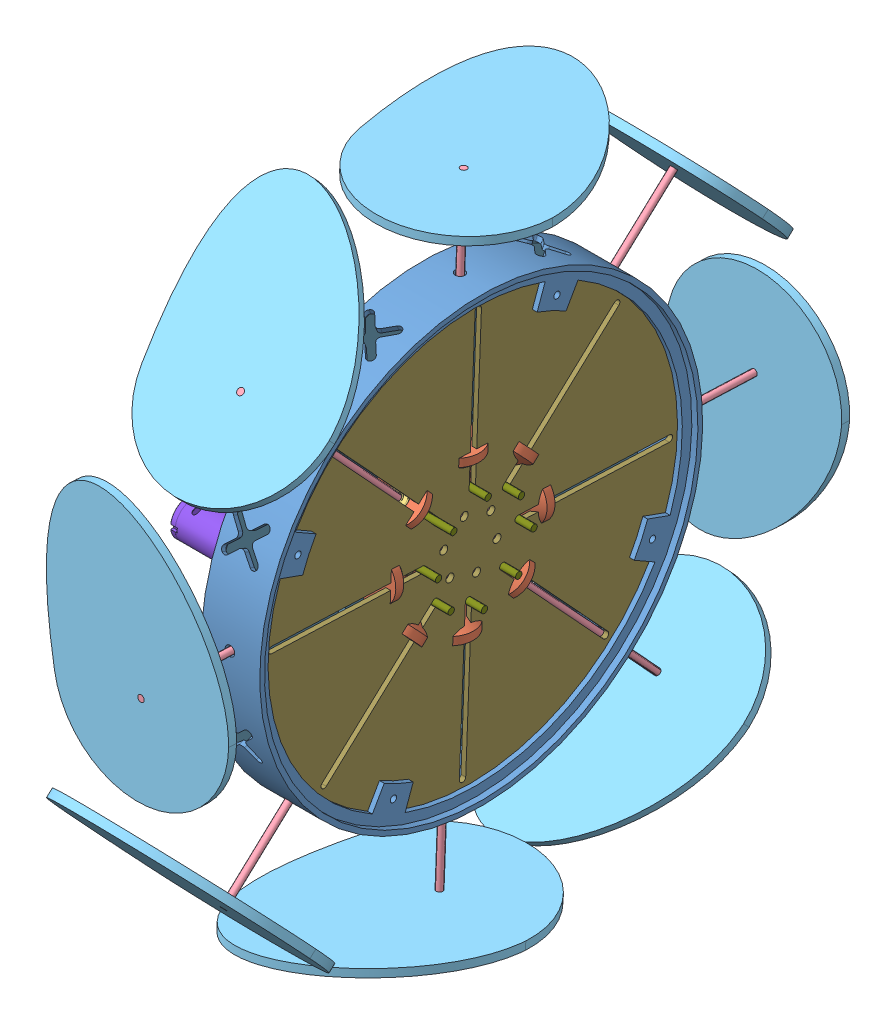
SolidWorks assembly armadillo-assembly, configuration Default. Lengths in mm.
Overall size (240.54 455.24 455.24).
84 component instances, 23 part files, 72 mates.
Components (placement in the parent):
- gear-plate-1: gear-plate [Default] at (127.9331 88.8526 55.989) size (3.8 120 80.27)
- 3mm-standoff-1: 3mm-standoff [Default] at (131.7331 77.626 -41.0696) size (22.7 6.93 6)
- 3mm-standoff-2: 3mm-standoff [Default] at (131.7331 15.626 23.2006) size (22.7 6.93 6)
- 3mm-standoff-3: 3mm-standoff [Default] at (131.7331 -26.374 -41.0696) size (22.7 6.93 6)
- gear-plate-2-1: gear-plate-2 [Default] at (154.4331 41.064 40.1689) size (3.8 120 80.27)
- 56-spur-2-1: 56-spur-2 [Default] at (146.1331 70.439 53.9289) x (-1 0 0) z (0 0.20976 -0.977753) size (21.9 85.49 85.49)
- 38-spur-2-2: 38-spur-2 [Default] at (146.0331 13.4884 13.6588) x (-1 0 0) z (0 -0.380955 0.924594) size (22.6 59.99 59.98)
- 25-tooth-spur-1: 25-tooth-spur [Default] at (134.0331 -9.561 53.9289) x (1 0 0) z (0 -0.929032 0.37) size (27.6 38.56 38.56)
- 30mm-3mm-standoff-1: 30mm-3mm-standoff [Default] at (97.9331 66.6963 -2.0848) size (30 6.93 6)
- 30mm-3mm-standoff-2: 30mm-3mm-standoff [Default] at (97.9331 66.6963 24.486) size (30 6.93 6)
- 30mm-3mm-standoff-3: 30mm-3mm-standoff [Default] at (97.9331 43.6853 11.2006) size (30 6.93 6)
- 30mm-3mm-standoff-4: 30mm-3mm-standoff [Default] at (97.9331 -15.4443 -2.0848) size (30 6.93 6)
- 30mm-3mm-standoff-5: 30mm-3mm-standoff [Default] at (127.9331 27.0214 87.9785) x (-1 0 0) z (0 -0.924225 -0.381849) size (30 6.93 6)
- 30mm-3mm-standoff-6: 30mm-3mm-standoff [Default] at (127.9331 50.0324 74.693) x (-1 0 0) z (0 -0.924225 -0.381849) size (30 6.93 6)
- motor-1: motor [Default] at (85.2831 63.839 53.9289) x (0 0 -1) z (0 -1 0) size (36.71 72.01 36.7)
- motor-2: motor [Default] at (85.2831 -2.961 53.9289) x (0 0 1) z (0 1 0) size (36.71 72.01 36.7)
- 6mm-coupler-1: 6mm-coupler [Default] at (92.9527 68.4137 78.816) x (0 -0.56228 -0.826947) z (1 0 0) size (15.04 15.04 20.11)
- gear-holder-1: gear-holder [Default] at (144.1331 70.439 53.9289) x (0 -0.977753 -0.20976) z (-1 0 0) size (75 75 12)
- shaft-1: shaft [Default] at (161.3831 70.439 53.9289) x (0 0.999313 0.03706) z (-1 0 0) size (6 6 100)
- facePlate-2.0-1: facePlate-2.0 [Default] at (211.3831 70.439 53.9289) x (0 0.678648 -0.734463) z (1 0 0) size (270 270 3)
- flange-coupling-1: flange-coupling [Default] at (207.3831 70.439 53.9289) x (0 0.678648 -0.734463) z (1 0 0) size (47 47 20)
- clutchPlate-2.0-1: clutchPlate-2.0 [Default] at (185.8831 70.439 53.9289) x (0 0.741879 0.670534) z (1 0 0) size (270 270 3.5)
- 40MM-3MM-STANDOFF-1: 40MM-3MM-STANDOFF [Default] at (144.1331 72.5384 32.6125) size (40 6.93 6)
- 40MM-3MM-STANDOFF-2: 40MM-3MM-STANDOFF [Default] at (144.1331 43.6265 6.481) size (40 6.93 6)
- 40MM-3MM-STANDOFF-3: 40MM-3MM-STANDOFF [Default] at (184.1331 123.1788 58.0008) x (-1 0 0) z (0 -0.924225 -0.381849) size (40 6.93 6)
- spoke-1: spoke [Default] at (199.3831 50.0786 75.9639) x (0 0.956269 0.292488) z (1 0 0) size (4 4 50)
- spoke-2: spoke [Default] at (199.3831 40.4609 55.113) x (0 -0.097119 0.995273) z (1 0 0) size (4 4 50)
- spoke-3: spoke [Default] at (199.3831 69.2549 23.9509) x (0 -0.097119 0.995273) z (1 0 0) size (4 4 50)
- spoke-4: spoke [Default] at (199.3831 48.404 33.5685) x (0 -0.097119 0.995273) z (1 0 0) size (4 4 50)
- spoke-5: spoke [Default] at (199.3831 90.7995 31.894) x (0 -0.097119 0.995273) z (1 0 0) size (4 4 50)
- spoke-6: spoke [Default] at (199.3831 92.474 74.2894) x (0 -0.097119 0.995273) z (1 0 0) size (4 4 50)
- spoke-7: spoke [Default] at (199.3831 100.4171 52.7449) x (0 -0.097119 0.995273) z (1 0 0) size (4 4 50)
- spoke-8: spoke [Default] at (199.3831 71.6231 83.907) x (0 -0.097119 0.995273) z (1 0 0) size (4 4 50)
- idler-gear-pin-1: idler-gear-pin [Default] at (143.9331 13.4884 13.6588) x (0 0 -1) z (1 0 0) size (6 6 40)
- actuation-shaft-2: actuation-shaft [Default] at (133.8831 -9.561 53.9289) x (0 0 -1) z (1 0 0) size (6 6 60)
- casing-1: casing [Default] at (217.3831 70.439 53.9289) x (-1 0 0) z (0 -0.418848 -0.908056) size (36.8 278 278)
- legs-1: legs [Default] at (175.4611 117.5432 79.7673) x (0 -0.678648 0.734463) z (1 0 0) size (189.45 175.5 148.14)
  - double-bearing-1: double-bearing [Default] at (12.9899 7.13 27.047) x (0 1 0) z (1 0 0) size (30.5 30.1 30.39)
  - 624RS-1: 624RS [Default] at (12.9899 22.13 26.047) size (13 13 5)
  - 624RS-2: 624RS [Default] at (12.9899 2.13 27.047) x (1 0 0) z (0 1 0) size (13 13 5)
  - shell-spoke-1: shell-spoke [Default] at (12.9899 -92.87 27.047) x (-0.999501 0 -0.031598) z (0 1 0) size (4 4 150)
  - shell-mockup-1: shell-mockup [Default] at (12.9899 -142.87 27.047) x (0.200645 0 -0.979664) z (0 1 0) size (116.49 169.53 5)
- legs-2: legs [Default] at (175.4611 122.0172 38.8917) x (0 0.039467 0.999221) z (1 0 0) size (189.45 175.5 148.14)
  - double-bearing-1: double-bearing [Default] at (12.9899 7.13 27.047) x (0 1 0) z (1 0 0) size (30.5 30.1 30.39)
  - 624RS-1: 624RS [Default] at (12.9899 22.13 26.047) size (13 13 5)
  - 624RS-2: 624RS [Default] at (12.9899 2.13 27.047) x (1 0 0) z (0 1 0) size (13 13 5)
  - shell-spoke-1: shell-spoke [Default] at (12.9899 -92.87 27.047) x (-0.999501 0 -0.031598) z (0 1 0) size (4 4 150)
  - shell-mockup-1: shell-mockup [Default] at (12.9899 -142.87 27.047) x (0.200645 0 -0.979664) z (0 1 0) size (116.49 169.53 5)
- legs-3: legs [Default] at (175.4611 96.2774 6.8247) x (0 0.734463 0.678648) z (1 0 0) size (189.45 175.5 148.14)
  - double-bearing-1: double-bearing [Default] at (12.9899 7.13 27.047) x (0 1 0) z (1 0 0) size (30.5 30.1 30.39)
  - 624RS-1: 624RS [Default] at (12.9899 22.13 26.047) size (13 13 5)
  - 624RS-2: 624RS [Default] at (12.9899 2.13 27.047) x (1 0 0) z (0 1 0) size (13 13 5)
  - shell-spoke-1: shell-spoke [Default] at (12.9899 -92.87 27.047) x (-0.999501 0 -0.031598) z (0 1 0) size (4 4 150)
  - shell-mockup-1: shell-mockup [Default] at (12.9899 -142.87 27.047) x (0.200645 0 -0.979664) z (0 1 0) size (116.49 169.53 5)
- legs-4: legs [Default] at (175.4611 55.4018 2.3508) x (0 0.999221 -0.039467) z (1 0 0) size (189.45 175.5 148.14)
  - double-bearing-1: double-bearing [Default] at (12.9899 7.13 27.047) x (0 1 0) z (1 0 0) size (30.5 30.1 30.39)
  - 624RS-1: 624RS [Default] at (12.9899 22.13 26.047) size (13 13 5)
  - 624RS-2: 624RS [Default] at (12.9899 2.13 27.047) x (1 0 0) z (0 1 0) size (13 13 5)
  - shell-spoke-1: shell-spoke [Default] at (12.9899 -92.87 27.047) x (-0.999501 0 -0.031598) z (0 1 0) size (4 4 150)
  - shell-mockup-1: shell-mockup [Default] at (12.9899 -142.87 27.047) x (0.200645 0 -0.979664) z (0 1 0) size (116.49 169.53 5)
- legs-5: legs [Default] at (175.4611 23.3348 28.0906) x (0 0.678648 -0.734463) z (1 0 0) size (189.45 175.5 148.14)
  - double-bearing-1: double-bearing [Default] at (12.9899 7.13 27.047) x (0 1 0) z (1 0 0) size (30.5 30.1 30.39)
  - 624RS-1: 624RS [Default] at (12.9899 22.13 26.047) size (13 13 5)
  - 624RS-2: 624RS [Default] at (12.9899 2.13 27.047) x (1 0 0) z (0 1 0) size (13 13 5)
  - shell-spoke-1: shell-spoke [Default] at (12.9899 -92.87 27.047) x (-0.999501 0 -0.031598) z (0 1 0) size (4 4 150)
  - shell-mockup-1: shell-mockup [Default] at (12.9899 -142.87 27.047) x (0.200645 0 -0.979664) z (0 1 0) size (116.49 169.53 5)
- legs-6: legs [Default] at (175.4611 18.8608 68.9662) x (0 -0.039467 -0.999221) z (1 0 0) size (189.45 175.5 148.14)
  - double-bearing-1: double-bearing [Default] at (12.9899 7.13 27.047) x (0 1 0) z (1 0 0) size (30.5 30.1 30.39)
  - 624RS-1: 624RS [Default] at (12.9899 22.13 26.047) size (13 13 5)
  - 624RS-2: 624RS [Default] at (12.9899 2.13 27.047) x (1 0 0) z (0 1 0) size (13 13 5)
  - shell-spoke-1: shell-spoke [Default] at (12.9899 -92.87 27.047) x (-0.999501 0 -0.031598) z (0 1 0) size (4 4 150)
  - shell-mockup-1: shell-mockup [Default] at (12.9899 -142.87 27.047) x (0.200645 0 -0.979664) z (0 1 0) size (116.49 169.53 5)
- legs-7: legs [Default] at (175.4611 44.6007 101.0332) x (0 -0.734463 -0.678648) z (1 0 0) size (189.45 175.5 148.14)
  - double-bearing-1: double-bearing [Default] at (12.9899 7.13 27.047) x (0 1 0) z (1 0 0) size (30.5 30.1 30.39)
  - 624RS-1: 624RS [Default] at (12.9899 22.13 26.047) size (13 13 5)
  - 624RS-2: 624RS [Default] at (12.9899 2.13 27.047) x (1 0 0) z (0 1 0) size (13 13 5)
  - shell-spoke-1: shell-spoke [Default] at (12.9899 -92.87 27.047) x (-0.999501 0 -0.031598) z (0 1 0) size (4 4 150)
  - shell-mockup-1: shell-mockup [Default] at (12.9899 -142.87 27.047) x (0.200645 0 -0.979664) z (0 1 0) size (116.49 169.53 5)
- legs-8: legs [Default] at (175.4611 85.4762 105.5071) x (0 -0.999221 0.039467) z (1 0 0) size (189.45 175.5 148.14)
  - double-bearing-1: double-bearing [Default] at (12.9899 7.13 27.047) x (0 1 0) z (1 0 0) size (30.5 30.1 30.39)
  - 624RS-1: 624RS [Default] at (12.9899 22.13 26.047) size (13 13 5)
  - 624RS-2: 624RS [Default] at (12.9899 2.13 27.047) x (1 0 0) z (0 1 0) size (13 13 5)
  - shell-spoke-1: shell-spoke [Default] at (12.9899 -92.87 27.047) x (-0.999501 0 -0.031598) z (0 1 0) size (4 4 150)
  - shell-mockup-1: shell-mockup [Default] at (12.9899 -142.87 27.047) x (0.200645 0 -0.979664) z (0 1 0) size (116.49 169.53 5)
Mates (geometry in assembly coordinates):
- Coincident1: coincident aligned: circle of gear-plate-1; circle of 3mm-standoff-1
- Coincident2: coincident aligned: circle of gear-plate-1; circle of 3mm-standoff-2
- Coincident3: coincident aligned: circle of gear-plate-1; circle of 3mm-standoff-3
- Concentric1: concentric aligned: circle of 3mm-standoff-1; circle of gear-plate-2-1
- Concentric2: concentric aligned: circle of 3mm-standoff-2; circle of gear-plate-2-1
- Coincident10: coincident anti-aligned: plane of 3mm-standoff-3 through (154.4331 -26.374 -41.0696) normal (1 0 0); plane of gear-plate-2-1 through (154.4331 70.439 53.9289) normal (-1 0 0)
- Coincident11: coincident anti-aligned: circle of gear-plate-1; circle of 56-spur-2-1
- Coincident12: coincident anti-aligned: circle of gear-plate-1; circle of 38-spur-2-2
- Concentric4: concentric aligned: circle of gear-plate-1; circle of 25-tooth-spur-1
- Coincident14: coincident aligned: plane of 38-spur-2-2 through (146.0331 13.4884 13.6588) normal (1 0 0); plane of 25-tooth-spur-1 through (146.0331 -9.561 53.9289) normal (1 0 0)
- GearMate1: gear = 38 : 56 mm: circle of 56-spur-2-1; circle of 38-spur-2-2
- GearMate2: gear = 38 : 25 mm: cylinder of 25-tooth-spur-1 through (146.0331 -9.561 53.9289) axis (-1 0 0) radius 3; cylinder of 38-spur-2-2 through (134.0331 13.4884 13.6588) axis (1 0 0) radius 3
- Coincident15: coincident aligned: circle of gear-plate-1; circle of 30mm-3mm-standoff-2
- Coincident16: coincident aligned: circle of gear-plate-1; circle of 30mm-3mm-standoff-3
- Coincident17: coincident aligned: circle of gear-plate-1; circle of 30mm-3mm-standoff-1
- Coincident18: coincident aligned: circle of gear-plate-1; circle of 30mm-3mm-standoff-4
- Coincident19: coincident anti-aligned: circle of gear-plate-1; circle of 30mm-3mm-standoff-6
- Coincident20: coincident anti-aligned: circle of gear-plate-1; circle of 30mm-3mm-standoff-5
- Concentric7: concentric aligned: circle of gear-plate-1; circle of motor-1
- Coincident22: coincident aligned: circle of 30mm-3mm-standoff-3; circle of motor-1
- Concentric8: concentric aligned: circle of 25-tooth-spur-1; circle of motor-2
- Coincident23: coincident anti-aligned: circle of 30mm-3mm-standoff-6; circle of motor-2
- Concentric9: concentric aligned: circle of motor-1; circle of 6mm-coupler-1
- Coincident24: coincident aligned: plane of motor-1 through (103.8831 63.839 53.9289) normal (-1 0 0); plane of 6mm-coupler-1 through (103.8831 70.439 53.9289) normal (-1 0 0)
- Concentric11: concentric anti-aligned: cylinder of 56-spur-2-1 through (153.6331 70.439 53.9289) axis (-1 0 0) radius 7.2; cylinder of gear-holder-1 through (140.1331 70.439 53.9289) axis (1 0 0) radius 7.2
- Coincident26: coincident anti-aligned: circle of 56-spur-2-1; circle of gear-holder-1
- Concentric12: concentric anti-aligned: cylinder of shaft-1 through (211.3831 70.439 53.9289) axis (-1 0 0) radius 3; circle of 6mm-coupler-1
- Coincident27: coincident aligned: plane of 6mm-coupler-1 through (111.3831 70.439 53.9289) normal (-1 0 0); plane of shaft-1 through (111.3831 70.439 53.9289) normal (-1 0 0)
- Concentric13: concentric aligned: cylinder of shaft-1 through (211.3831 70.439 53.9289) axis (-1 0 0) radius 3; circle of flange-coupling-1
- Coincident28: coincident aligned: plane of shaft-1 through (211.3831 70.439 53.9289) normal (1 0 0); plane of flange-coupling-1 through (211.3831 70.439 53.9289) normal (1 0 0)
- Coincident29: coincident aligned: circle of facePlate-2.0-1; circle of flange-coupling-1
- Coincident30: coincident aligned: circle of facePlate-2.0-1; circle of flange-coupling-1
- Concentric14: concentric anti-aligned: cylinder of shaft-1 through (211.3831 70.439 53.9289) axis (-1 0 0) radius 3; cylinder of clutchPlate-2.0-1 through (184.1331 70.439 53.9289) axis (1 0 0) radius 5
- Coincident31: coincident anti-aligned: circle of gear-holder-1; circle of 40MM-3MM-STANDOFF-1
- Coincident32: coincident anti-aligned: circle of gear-holder-1; circle of 40MM-3MM-STANDOFF-2
- Coincident33: coincident aligned: circle of gear-holder-1; circle of 40MM-3MM-STANDOFF-3
- Coincident34: coincident aligned: circle of clutchPlate-2.0-1; circle of 40MM-3MM-STANDOFF-1
- Slot1: slot anti-aligned: cylinder of spoke-1 through (174.3831 50.0786 75.9639) axis (1 0 0) radius 2; plane of facePlate-2.0-1 through (214.3831 51.5485 77.3201) normal (0 -0.734463 -0.678648); cylinder of facePlate-2.0-1 through (214.3831 50.0796 75.9628) axis (-1 0 0) radius 2
- Distance1: distance = 10 mm aligned: plane of facePlate-2.0-1 through (214.3831 70.439 53.9289) normal (1 0 0); plane of spoke-1 through (224.3831 50.0786 75.9639) normal (1 0 0)
- Slot2: slot aligned: cylinder of spoke-1 through (174.3831 50.0786 75.9639) axis (1 0 0) radius 2; cylinder of clutchPlate-2.0-1 through (184.1331 154.2557 -38.8059) axis (1 0 0) radius 153; cylinder of clutchPlate-2.0-1 through (184.1331 -0.4049 -49.0572) axis (1 0 0) radius 2
- Slot3: slot anti-aligned: cylinder of spoke-2 through (174.3831 40.4609 55.113) axis (1 0 0) radius 2; plane of facePlate-2.0-1 through (214.3831 40.5413 57.1114) normal (0 -0.039467 -0.999221); cylinder of facePlate-2.0-1 through (214.3831 40.4624 55.113) axis (-1 0 0) radius 2
- Distance2: distance = 10 mm aligned: plane of facePlate-2.0-1 through (214.3831 70.439 53.9289) normal (1 0 0); plane of spoke-2 through (224.3831 40.4609 55.113) normal (1 0 0)
- Slot4: slot aligned: cylinder of spoke-2 through (174.3831 40.4609 55.113) axis (1 0 0) radius 2; cylinder of clutchPlate-2.0-1 through (184.1331 195.2798 47.6228) axis (1 0 0) radius 157; cylinder of clutchPlate-2.0-1 through (184.1331 93.167 -68.9875) axis (1 0 0) radius 2
- Slot5: slot anti-aligned: cylinder of spoke-4 through (174.3831 48.404 33.5685) axis (1 0 0) radius 2; plane of facePlate-2.0-1 through (214.3831 47.0478 35.0384) normal (0 0.678648 -0.734463); cylinder of facePlate-2.0-1 through (214.3831 48.4051 33.5695) axis (-1 0 0) radius 2
- Slot6: slot aligned: cylinder of spoke-4 through (174.3831 48.404 33.5685) axis (1 0 0) radius 2; cylinder of clutchPlate-2.0-1 through (184.1331 163.1739 137.7456) axis (1 0 0) radius 157; cylinder of clutchPlate-2.0-1 through (184.1331 173.4251 -16.915) axis (1 0 0) radius 2
- Slot7: slot anti-aligned: cylinder of spoke-3 through (174.3831 69.2549 23.9509) axis (1 0 0) radius 2; plane of facePlate-2.0-1 through (214.3831 67.2566 24.0313) normal (0 0.999221 -0.039467); cylinder of facePlate-2.0-1 through (214.3831 69.255 23.9523) axis (-1 0 0) radius 2
- Slot8: slot aligned: cylinder of clutchPlate-2.0-1 through (184.1331 76.7451 178.7698) axis (1 0 0) radius 157; cylinder of spoke-3 through (174.3831 69.2549 23.9509) axis (1 0 0) radius 2; cylinder of clutchPlate-2.0-1 through (184.1331 193.3554 76.6569) axis (1 0 0) radius 2
- Distance3: distance = 10 mm aligned: plane of spoke-4 through (224.3831 48.404 33.5685) normal (1 0 0); plane of facePlate-2.0-1 through (214.3831 70.439 53.9289) normal (1 0 0)
- Distance4: distance = 10 mm aligned: plane of spoke-3 through (224.3831 69.2549 23.9509) normal (1 0 0); plane of facePlate-2.0-1 through (214.3831 70.439 53.9289) normal (1 0 0)
- Slot9: slot anti-aligned: cylinder of spoke-5 through (174.3831 90.7995 31.894) axis (1 0 0) radius 2; plane of facePlate-2.0-1 through (214.3831 92.2674 33.2523) normal (0 -0.734463 -0.678648); cylinder of facePlate-2.0-1 through (214.3831 155.2701 -37.879) axis (-1 0 0) radius 2
- Slot10: slot aligned: cylinder of spoke-5 through (174.3831 90.7995 31.894) axis (1 0 0) radius 2; cylinder of clutchPlate-2.0-1 through (184.1331 -13.3777 146.6638) axis (1 0 0) radius 153; cylinder of clutchPlate-2.0-1 through (184.1331 141.2829 156.915) axis (1 0 0) radius 2
- Slot11: slot anti-aligned: plane of facePlate-2.0-1 through (214.3831 100.4946 54.7434) normal (0 -0.039467 -0.999221); cylinder of spoke-7 through (174.3831 100.4171 52.7449) axis (1 0 0) radius 2; cylinder of facePlate-2.0-1 through (214.3831 195.3416 48.9956) axis (-1 0 0) radius 2
- Slot12: slot aligned: cylinder of spoke-7 through (174.3831 100.4171 52.7449) axis (1 0 0) radius 2; cylinder of clutchPlate-2.0-1 through (184.1331 -54.4018 60.2351) axis (1 0 0) radius 153; cylinder of clutchPlate-2.0-1 through (184.1331 47.7111 176.8453) axis (1 0 0) radius 2
- Slot13: slot anti-aligned: cylinder of spoke-6 through (174.3831 92.474 74.2894) axis (1 0 0) radius 2; plane of facePlate-2.0-1 through (214.3831 91.1156 75.7573) normal (0 0.678648 -0.734463); cylinder of facePlate-2.0-1 through (214.3831 162.2469 138.76) axis (-1 0 0) radius 2
- Slot14: slot aligned: cylinder of spoke-6 through (174.3831 92.474 74.2894) axis (1 0 0) radius 2; cylinder of clutchPlate-2.0-1 through (184.1331 -22.2959 -29.8878) axis (1 0 0) radius 153; cylinder of clutchPlate-2.0-1 through (184.1331 -32.5471 124.7729) axis (1 0 0) radius 2
- Slot15: slot anti-aligned: cylinder of spoke-8 through (174.3831 71.6231 83.907) axis (1 0 0) radius 2; plane of facePlate-2.0-1 through (214.3831 69.6246 83.9845) normal (0 0.999221 -0.039467); cylinder of facePlate-2.0-1 through (214.3831 75.3724 178.8316) axis (-1 0 0) radius 2
- Slot16: slot aligned: cylinder of spoke-8 through (174.3831 71.6231 83.907) axis (1 0 0) radius 2; cylinder of clutchPlate-2.0-1 through (184.1331 64.1329 -70.9119) axis (1 0 0) radius 153; cylinder of clutchPlate-2.0-1 through (184.1331 -52.4774 31.201) axis (1 0 0) radius 2
- Distance5: distance = 10 mm aligned: plane of spoke-8 through (224.3831 71.6231 83.907) normal (1 0 0); plane of facePlate-2.0-1 through (214.3831 70.439 53.9289) normal (1 0 0)
- Distance7: distance = 10 mm aligned: plane of facePlate-2.0-1 through (214.3831 70.439 53.9289) normal (1 0 0); plane of spoke-6 through (224.3831 92.474 74.2894) normal (1 0 0)
- Distance8: distance = 10 mm aligned: plane of facePlate-2.0-1 through (214.3831 70.439 53.9289) normal (1 0 0); plane of spoke-7 through (224.3831 100.4171 52.7449) normal (1 0 0)
- Distance9: distance = 10 mm aligned: plane of facePlate-2.0-1 through (214.3831 70.439 53.9289) normal (1 0 0); plane of spoke-5 through (224.3831 90.7995 31.894) normal (1 0 0)
- Concentric17: concentric aligned: circle of idler-gear-pin-1; circle of gear-plate-1
- Distance10: distance = 4 mm aligned: plane of gear-plate-1 through (127.9331 88.8526 55.989) normal (-1 0 0); plane of idler-gear-pin-1 through (123.9331 13.4884 13.6588) normal (-1 0 0)
- Concentric18: concentric anti-aligned: cylinder of 25-tooth-spur-1 through (146.0331 -9.561 53.9289) axis (-1 0 0) radius 3; cylinder of actuation-shaft-2 through (103.8831 -9.561 53.9289) axis (1 0 0) radius 3
- Coincident40: coincident anti-aligned: plane of motor-2 through (103.8831 -2.961 53.9289) normal (-1 0 0); circle of actuation-shaft-2
- Concentric19: concentric anti-aligned: circle of facePlate-2.0-1; circle of casing-1
- Concentric20: concentric anti-aligned: circle of facePlate-2.0-1; circle of casing-1
- Coincident41: coincident anti-aligned: plane of facePlate-2.0-1 through (214.3831 70.439 53.9289) normal (1 0 0); plane of casing-1 through (214.3831 70.439 53.9289) normal (-1 0 0)
- Concentric30: concentric aligned: cylinder of spoke-7 through (174.3831 100.4365 52.7441) axis (1 0 0) radius 2; cylinder of legs-1/double-bearing-1 through (181.6172 100.4365 52.7441) axis (1 0 0) radius 2.05
- Concentric31: concentric aligned: cylinder of spoke-6 through (174.3831 92.474 74.2894) axis (1 0 0) radius 2; cylinder of legs-1/double-bearing-1 through (198.5081 92.474 74.2894) axis (1 0 0) radius 2.05
- Parallel16: parallel aligned: plane of facePlate-2.0-1 through (214.3831 93.8302 72.8195) normal (0 -0.678648 0.734463); plane of legs-1 through (175.4611 117.5432 79.7673) normal (0 -0.678648 0.734463)
- Width1: width: plane of clutchPlate-2.0-1 through (187.6331 70.439 53.9289) normal (1 0 0); plane of casing-1 through (217.3831 70.439 53.9289) normal (1 0 0); cylinder of legs-1/shell-spoke-1 through (202.5081 213.6604 186.2664) axis (0 -0.734463 -0.678648) radius 2
